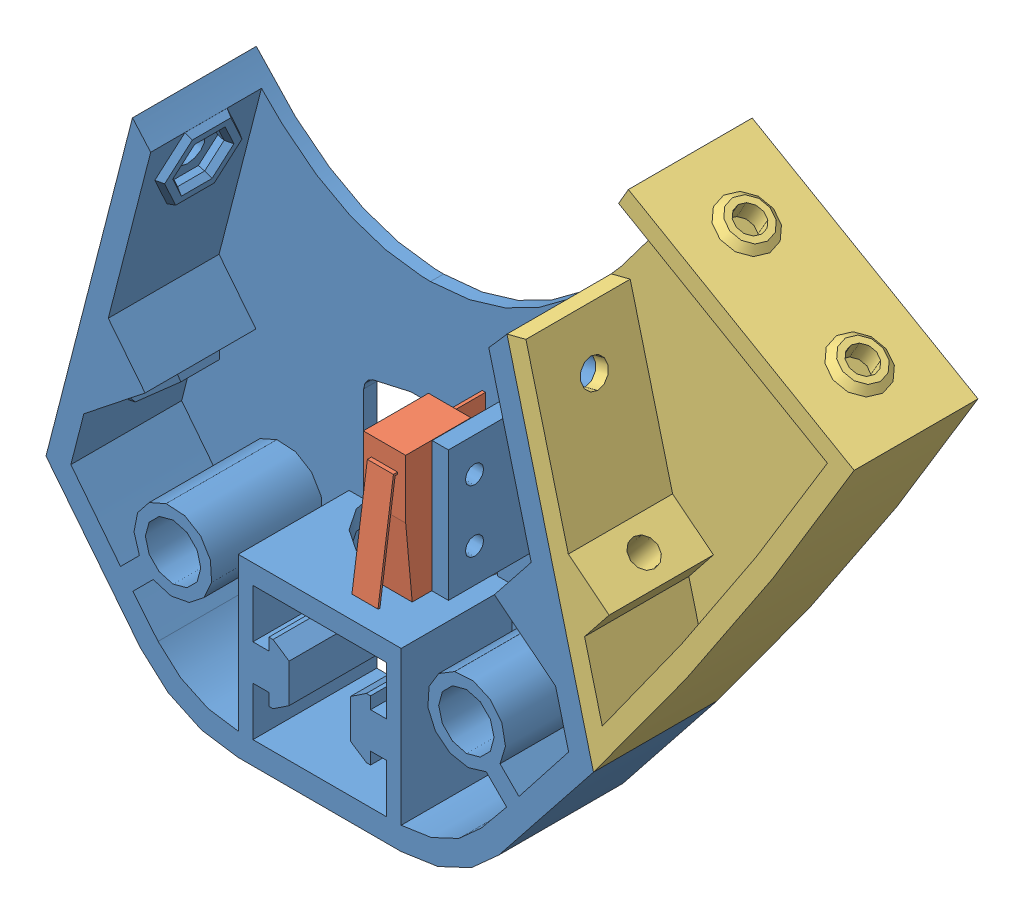
SolidWorks assembly Top Triangle Assembly, configuration Default. Lengths in mm.
Overall size (136.02 112.52 24).
3 component instances, 3 part files, 5 mates.
Components (placement in the parent):
- 3DR Bottom Motor Mount-1: 3DR Bottom Motor Mount [Top Microswitch] at origin size (84 76.89 19)
- Microswitch-1: Microswitch [Default] at (11.9363 31.25 11) x (0 1 0) z (1 0 0) size (20 18 6.5)
- Wings-1: Wings [Top With Dimples] at (42.1437 10.9951 0) x (0.968477 0.249105 0) z (0 0 1) size (53.71 76.24 19)
Mates (geometry in assembly coordinates):
- Concentric1: concentric anti-aligned: cylinder of 3DR Bottom Motor Mount-1 through (42.001 26.5 13) axis (-1 0 0) radius 1.4; cylinder of Microswitch-1 through (8.6863 26.5 13) axis (1 0 0) radius 1.25
- Concentric2: concentric anti-aligned: cylinder of 3DR Bottom Motor Mount-1 through (42.001 36 13) axis (-1 0 0) radius 1.4; cylinder of Microswitch-1 through (8.6863 36 13) axis (1 0 0) radius 1.25
- Coincident1: coincident aligned: plane of 3DR Bottom Motor Mount-1 through (-12.5 -13.75 0) normal (0 0 -1); plane of Wings-1 through (-409.8106 355.6043 0) normal (0 0 -1)
- Coincident2: coincident anti-aligned: plane of 3DR Bottom Motor Mount-1 through (28.7322 63.1367 19) normal (0.968477 0.249105 0); plane of Wings-1 through (28.7322 63.1367 3) normal (-0.968477 -0.249105 0)
- Coincident3: coincident: point of 3DR Bottom Motor Mount-1; line of Wings-1 through (42 11.5538 19) axis (0 0 -1)
